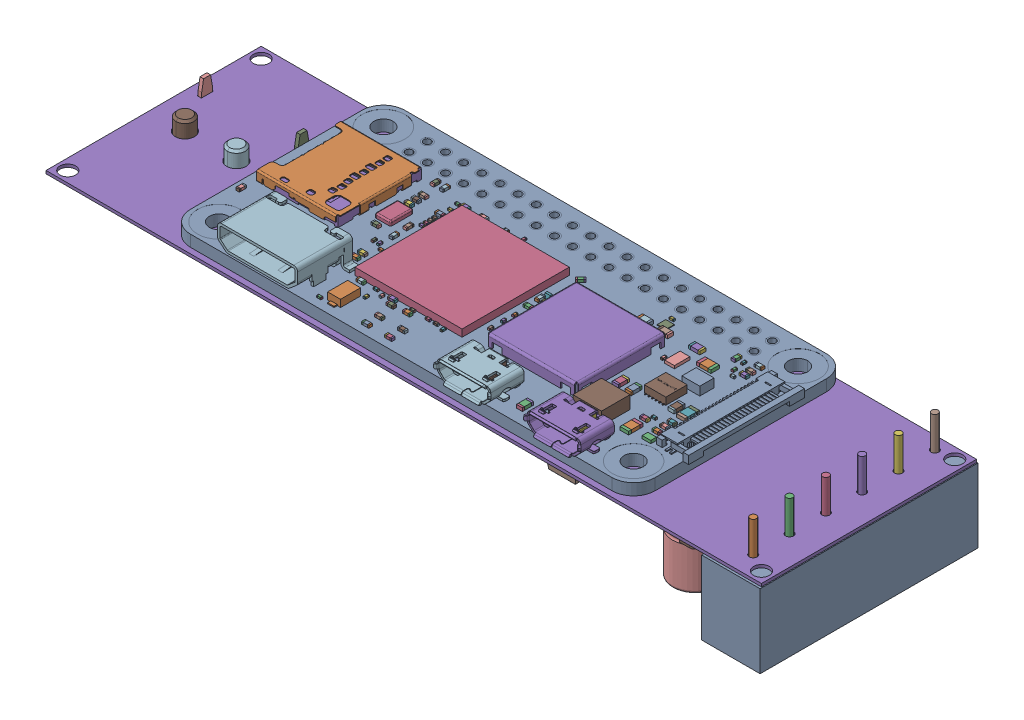
SolidWorks assembly pcb, configuration cage. Lengths in mm.
Overall size (100.11 16.86 31.05).
60 component instances, 5 part files, 37 mates.
Components (placement in the parent):
- Raspberry Pi Zero 2 W-1: Raspberry Pi Zero 2 W [Default] at origin size (65.8 5.05 30.58)
- custom_pcb-1: custom_pcb [Default] at (-49.911 -2.2115 14.789) x (1 0 0) z (0 -1 0) size (100.11 30.48 15.4)
- spacer-2: spacer [m3 1-8] at (-29 -3.975 11.5) x (0.982082 0 -0.188455) z (0.188455 0 0.982082) (suppressed, hidden)
- spacer-5: spacer [m3 0.4] at (-29 -14.5465 -11.5) x (0.8 0 -0.6) z (0.6 0 0.8) (suppressed, hidden)
- spacer-6: spacer [m3 0.4] at (29 -14.5465 -11.5) x (0.672593 0 -0.740013) z (0.740013 0 0.672593) (suppressed, hidden)
- spacer-7: spacer [m3 0.4] at (29 -14.5465 11.5) x (0.497251 0 -0.867606) z (0.867606 0 0.497251) (suppressed, hidden)
- spacer-8: spacer [m3 0.4] at (-29 -14.5465 11.5) x (0.28 0 -0.96) z (0.96 0 0.28) (suppressed, hidden)
- DRV8871-1: DRV8871 [Default] at (-7.62 8.6837 12.7) x (-1 0 0) z (0 1 0) (suppressed, hidden)
- plate-1: plate [Default] at (0 4.7588 0) (suppressed, hidden)
- spacer-17: spacer [m3 1-32] at (-29 3.965 11.5) x (-0.952427 0 0.304765) z (-0.304765 0 -0.952427) (suppressed, hidden)
- spacer-19: spacer [m3 1-32] at (-29 3.1713 11.5) x (-0.952427 0 0.304765) z (-0.304765 0 -0.952427) (suppressed, hidden)
- spacer-20: spacer [m3 1-32] at (-29 2.3775 11.5) x (-0.952427 0 0.304765) z (-0.304765 0 -0.952427) (suppressed, hidden)
- spacer-21: spacer [m3 1-32] at (-29 1.5837 11.5) x (-0.952427 0 0.304765) z (-0.304765 0 -0.952427) (suppressed, hidden)
- spacer-22: spacer [m3 1-32] at (-29 0.79 11.5) x (-0.952427 0 0.304765) z (-0.304765 0 -0.952427) (suppressed, hidden)
- spacer-23: spacer [m3 1-32] at (29 -1.5938 -11.5) x (0.982082 0 -0.188455) z (0.188455 0 0.982082) (suppressed, hidden)
- spacer-24: spacer [m3 1-32] at (29 -1.5938 11.5) x (0.982082 0 -0.188455) z (0.188455 0 0.982082) (suppressed, hidden)
- spacer-25: spacer [m3 1-32] at (-29 -1.5938 -11.5) x (0.982082 0 -0.188455) z (0.188455 0 0.982082) (suppressed, hidden)
- spacer-26: spacer [m3 1-32] at (29 3.965 -11.5) x (-0.952427 0 0.304765) z (-0.304765 0 -0.952427) (suppressed, hidden)
- spacer-27: spacer [m3 1-32] at (29 3.965 11.5) x (-0.952427 0 0.304765) z (-0.304765 0 -0.952427) (suppressed, hidden)
- spacer-28: spacer [m3 1-32] at (-29 3.965 -11.5) x (-0.952427 0 0.304765) z (-0.304765 0 -0.952427) (suppressed, hidden)
- spacer-29: spacer [m3 1-32] at (29 3.1713 -11.5) x (-0.952427 0 0.304765) z (-0.304765 0 -0.952427) (suppressed, hidden)
- spacer-30: spacer [m3 1-32] at (29 3.1713 11.5) x (-0.952427 0 0.304765) z (-0.304765 0 -0.952427) (suppressed, hidden)
- spacer-31: spacer [m3 1-32] at (-29 3.1713 -11.5) x (-0.952427 0 0.304765) z (-0.304765 0 -0.952427) (suppressed, hidden)
- spacer-32: spacer [m3 1-32] at (29 2.3775 -11.5) x (-0.952427 0 0.304765) z (-0.304765 0 -0.952427) (suppressed, hidden)
- spacer-33: spacer [m3 1-32] at (29 2.3775 11.5) x (-0.952427 0 0.304765) z (-0.304765 0 -0.952427) (suppressed, hidden)
- spacer-34: spacer [m3 1-32] at (-29 2.3775 -11.5) x (-0.952427 0 0.304765) z (-0.304765 0 -0.952427) (suppressed, hidden)
- spacer-35: spacer [m3 1-32] at (29 1.5837 -11.5) x (-0.952427 0 0.304765) z (-0.304765 0 -0.952427) (suppressed, hidden)
- spacer-36: spacer [m3 1-32] at (29 1.5837 11.5) x (-0.952427 0 0.304765) z (-0.304765 0 -0.952427) (suppressed, hidden)
- spacer-37: spacer [m3 1-32] at (-29 1.5837 -11.5) x (-0.952427 0 0.304765) z (-0.304765 0 -0.952427) (suppressed, hidden)
- spacer-38: spacer [m3 1-32] at (29 0.79 -11.5) x (-0.952427 0 0.304765) z (-0.304765 0 -0.952427) (suppressed, hidden)
- spacer-39: spacer [m3 1-32] at (29 0.79 11.5) x (-0.952427 0 0.304765) z (-0.304765 0 -0.952427) (suppressed, hidden)
- spacer-40: spacer [m3 1-32] at (-29 0.79 -11.5) x (-0.952427 0 0.304765) z (-0.304765 0 -0.952427) (suppressed, hidden)
- spacer-45: spacer [m2 1-32] at (-15.24 7.14 3.175) x (-0.952427 0 0.304765) z (-0.304765 0 -0.952427) (suppressed, hidden)
- DRV8871-7: DRV8871 [Default] at (13.97 8.6837 12.7) x (-1 0 0) z (0 1 0) (suppressed, hidden)
- spacer-51: spacer [m2 1-32] at (-15.24 6.3463 3.175) x (-0.952427 0 0.304765) z (-0.304765 0 -0.952427) (suppressed, hidden)
- spacer-52: spacer [m2 1-32] at (30.48 8.7275 3.4925) x (0.400623 0 0.916243) z (-0.916243 0 0.400623) (suppressed, hidden)
- spacer-53: spacer [m2 1-32] at (30.48 8.7275 18.7325) x (0.400623 0 0.916243) z (-0.916243 0 0.400623) (suppressed, hidden)
- spacer-54: spacer [m2 1-32] at (30.48 8.7275 -18.7325) x (0.400623 0 0.916243) z (-0.916243 0 0.400623) (suppressed, hidden)
- spacer-55: spacer [m2 1-32] at (30.48 8.7275 -3.4925) x (0.400623 0 0.916243) z (-0.916243 0 0.400623) (suppressed, hidden)
- spacer-56: spacer [m2 1-32] at (5.08 8.7275 -18.7325) x (0.400623 0 0.916243) z (-0.916243 0 0.400623) (suppressed, hidden)
- spacer-57: spacer [m2 1-32] at (30.48 7.9337 3.4925) x (0.400623 0 0.916243) z (-0.916243 0 0.400623) (suppressed, hidden)
- spacer-58: spacer [m2 1-32] at (30.48 7.9337 18.7325) x (0.400623 0 0.916243) z (-0.916243 0 0.400623) (suppressed, hidden)
- spacer-59: spacer [m2 1-32] at (30.48 7.9337 -18.7325) x (0.400623 0 0.916243) z (-0.916243 0 0.400623) (suppressed, hidden)
- spacer-60: spacer [m2 1-32] at (30.48 7.9337 -3.4925) x (0.400623 0 0.916243) z (-0.916243 0 0.400623) (suppressed, hidden)
- spacer-61: spacer [m2 1-32] at (5.08 7.9337 -18.7325) x (0.400623 0 0.916243) z (-0.916243 0 0.400623) (suppressed, hidden)
- spacer-62: spacer [m2 1-32] at (21.59 7.14 -3.175) x (-0.952427 0 0.304765) z (-0.304765 0 -0.952427) (suppressed, hidden)
- spacer-63: spacer [m2 1-32] at (6.35 7.14 -3.175) x (-0.952427 0 0.304765) z (-0.304765 0 -0.952427) (suppressed, hidden)
- spacer-64: spacer [m2 1-32] at (0 7.14 3.175) x (-0.952427 0 0.304765) z (-0.304765 0 -0.952427) (suppressed, hidden)
- spacer-65: spacer [m2 1-32] at (-15.24 7.14 -3.175) x (-0.952427 0 0.304765) z (-0.304765 0 -0.952427) (suppressed, hidden)
- spacer-66: spacer [m2 1-32] at (0 7.14 -3.175) x (-0.952427 0 0.304765) z (-0.304765 0 -0.952427) (suppressed, hidden)
- spacer-67: spacer [m2 1-32] at (21.59 6.3463 -3.175) x (-0.952427 0 0.304765) z (-0.304765 0 -0.952427) (suppressed, hidden)
- spacer-68: spacer [m2 1-32] at (6.35 6.3463 -3.175) x (-0.952427 0 0.304765) z (-0.304765 0 -0.952427) (suppressed, hidden)
- spacer-69: spacer [m2 1-32] at (0 6.3463 3.175) x (-0.952427 0 0.304765) z (-0.304765 0 -0.952427) (suppressed, hidden)
- spacer-70: spacer [m2 1-32] at (-15.24 6.3463 -3.175) x (-0.952427 0 0.304765) z (-0.304765 0 -0.952427) (suppressed, hidden)
- spacer-71: spacer [m2 1-32] at (0 6.3463 -3.175) x (-0.952427 0 0.304765) z (-0.304765 0 -0.952427) (suppressed, hidden)
- DRV8871-9: DRV8871 [Default] at (13.97 8.6837 -12.7) x (1 0 0) z (0 1 0) (suppressed, hidden)
- spacer-72: spacer [m2 1-32] at (21.59 7.14 3.175) x (-0.952427 0 0.304765) z (-0.304765 0 -0.952427) (suppressed, hidden)
- spacer-73: spacer [m2 1-32] at (6.35 7.14 3.175) x (-0.952427 0 0.304765) z (-0.304765 0 -0.952427) (suppressed, hidden)
- spacer-74: spacer [m2 1-32] at (21.59 6.3463 3.175) x (-0.952427 0 0.304765) z (-0.304765 0 -0.952427) (suppressed, hidden)
- spacer-75: spacer [m2 1-32] at (6.35 6.3463 3.175) x (-0.952427 0 0.304765) z (-0.304765 0 -0.952427) (suppressed, hidden)
Mates (geometry in assembly coordinates):
- Coincident30: coordinate: point of Raspberry Pi Zero 2 W-1
- Concentric1: concentric aligned: cylinder of Raspberry Pi Zero 2 W-1 through (-24.13 0.8 -12.77) axis (0 1 0) radius 0.5; cylinder of custom_pcb-1 through (-24.13 -1.8 -12.77) axis (0 1 0) radius 0.555
- Parallel1: parallel aligned: plane of Raspberry Pi Zero 2 W-1 through (-32.5 0.8 -15) normal (0 0 -1); plane of custom_pcb-1 through (-49.911 -1.8 -15.31) normal (0 0 -1)
- Coincident33: coincident anti-aligned: plane of Raspberry Pi Zero 2 W-1 through (0 -0.8 0) normal (0 -1 0); plane of spacer-2 through (-29 -0.8 11.5) normal (0 1 0)
- Coincident34: coincident anti-aligned: plane of custom_pcb-1 through (0.127 -1.8 -0.2605) normal (0 1 0); plane of spacer-2 through (-29 -3.975 11.5) normal (0 -1 0)
- Concentric4: concentric anti-aligned: cylinder of Raspberry Pi Zero 2 W-1 through (-29 0.8 11.5) axis (0 1 0) radius 1.35; cylinder of spacer-2 through (-29 -0.8 11.5) axis (0 -1 0) radius 3.175
- Coincident39: coincident anti-aligned: plane of custom_pcb-1 through (0.127 -2.2115 -0.2605) normal (0 -1 0); plane of spacer-5 through (-29 -4.3865 -11.5) normal (0 1 0)
- Coincident40: coincident anti-aligned: plane of custom_pcb-1 through (0.127 -2.2115 -0.2605) normal (0 -1 0); plane of spacer-6 through (29 -4.3865 -11.5) normal (0 1 0)
- Coincident41: coincident anti-aligned: plane of custom_pcb-1 through (0.127 -2.2115 -0.2605) normal (0 -1 0); plane of spacer-7 through (29 -4.3865 11.5) normal (0 1 0)
- Coincident42: coincident anti-aligned: plane of custom_pcb-1 through (0.127 -2.2115 -0.2605) normal (0 -1 0); plane of spacer-8 through (-29 -4.3865 11.5) normal (0 1 0)
- Concentric10: concentric aligned: cylinder of spacer-2 through (-29 -0.8 11.5) axis (0 -1 0) radius 3.175; cylinder of spacer-8 through (-29 -4.3865 11.5) axis (0 -1 0) radius 3.175
- Concentric12: concentric aligned: cylinder of Raspberry Pi Zero 2 W-1 through (-29 0.8 11.5) axis (0 1 0) radius 1.35; cylinder of plate-1 through (-29 6.3463 11.5) axis (0 1 0) radius 1.7
- Parallel2: parallel aligned: plane of Raspberry Pi Zero 2 W-1 through (-32.5 0.8 15) normal (0 0 1); plane of plate-1 through (-34.925 6.3463 22.225) normal (0 0 1)
- Coincident48: coincident anti-aligned: plane of plate-1 through (0 4.7588 0) normal (0 -1 0); plane of spacer-17 through (-29 4.7588 11.5) normal (0 1 0)
- Concentric16: concentric anti-aligned: cylinder of plate-1 through (-29 6.3463 11.5) axis (0 1 0) radius 1.7; cylinder of spacer-17 through (-29 4.7588 11.5) axis (0 -1 0) radius 3.175
- Coincident53: coincident anti-aligned: plane of Raspberry Pi Zero 2 W-1 through (-29 0.79 11.5) normal (0 1 0); plane of spacer-22 through (-29 0.79 11.5) normal (0 -1 0)
- Coincident56: coincident anti-aligned: plane of DRV8871-1 through (-7.62 7.9337 12.7) normal (0 -1 0); plane of spacer-45 through (-15.24 7.9337 3.175) normal (0 1 0)
- Concentric21: concentric anti-aligned: cylinder of spacer-49 through (-6.8904 9.5213 7.6284) axis (0 1 0) radius 1.2; cylinder of DRV8871-7 through (21.59 9.4337 3.175) axis (0 -1 0) radius 1.27
- Coincident57: coincident anti-aligned: plane of spacer-49 through (-6.8904 9.5213 7.6284) normal (0 1 0); plane of DRV8871-7 through (13.97 7.9337 12.7) normal (0 -1 0)
- Coincident59: coincident anti-aligned: plane of plate-1 through (0 6.3463 0) normal (0 1 0); plane of spacer-51 through (-15.24 6.3463 3.175) normal (0 -1 0)
- Concentric23: concentric anti-aligned: cylinder of DRV8871-7 through (21.59 9.4337 3.175) axis (0 -1 0) radius 1.27; cylinder of spacer-55 through (30.48 9.5213 -3.4925) axis (0 1 0) radius 1.2
- Coincident60: coincident anti-aligned: plane of DRV8871-7 through (13.97 7.9337 12.7) normal (0 -1 0); plane of spacer-55 through (30.48 9.5213 -3.4925) normal (0 1 0)
- Concentric26: concentric anti-aligned: cylinder of DRV8871-7 through (6.35 9.4337 3.175) axis (0 -1 0) radius 1.27; cylinder of spacer-54 through (30.48 9.5213 -18.7325) axis (0 1 0) radius 1.2
- Concentric27: concentric anti-aligned: cylinder of DRV8871-1 through (-15.24 9.4337 3.175) axis (0 -1 0) radius 1.27; cylinder of spacer-56 through (5.08 9.5213 -18.7325) axis (0 1 0) radius 1.2
- Concentric29: concentric anti-aligned: cylinder of plate-1 through (-15.24 6.3463 3.175) axis (0 1 0) radius 0.8; cylinder of spacer-51 through (-15.24 7.14 3.175) axis (0 -1 0) radius 2.3813
- Concentric30: concentric aligned: cylinder of DRV8871-1 through (-15.24 9.4337 3.175) axis (0 -1 0) radius 1.27; cylinder of spacer-45 through (-15.24 7.9337 3.175) axis (0 -1 0) radius 2.3813
- Concentric31: concentric anti-aligned: cylinder of DRV8871-1 through (0 9.4337 3.175) axis (0 -1 0) radius 1.27; cylinder of spacer-64 through (0 7.9337 3.175) axis (0 1 0) radius 1.2
- Coincident63: coincident anti-aligned: plane of spacer-66 through (0 7.9337 -3.175) normal (0 1 0); plane of DRV8871-9 through (-3.4601 13.4664 -12.4261) normal (0 -1 0)
- Concentric34: concentric anti-aligned: cylinder of spacer-66 through (0 7.9337 -3.175) axis (0 1 0) radius 1.2; cylinder of DRV8871-9 through (0 9.4337 -3.175) axis (0 -1 0) radius 1.27
- Concentric35: concentric anti-aligned: cylinder of spacer-65 through (-15.24 7.9337 -3.175) axis (0 1 0) radius 1.2; cylinder of DRV8871-9 through (-15.24 9.4337 -3.175) axis (0 -1 0) radius 1.27
- Concentric36: concentric anti-aligned: cylinder of DRV8871-7 through (21.59 9.4337 3.175) axis (0 -1 0) radius 1.27; cylinder of spacer-72 through (21.59 7.9337 3.175) axis (0 1 0) radius 1.2
- Concentric37: concentric anti-aligned: cylinder of DRV8871-7 through (6.35 9.4337 3.175) axis (0 -1 0) radius 1.27; cylinder of spacer-73 through (6.35 7.9337 3.175) axis (0 1 0) radius 1.2
- Coincident64: coincident anti-aligned: plane of DRV8871-7 through (13.97 7.9337 12.7) normal (0 -1 0); plane of spacer-73 through (6.35 7.9337 3.175) normal (0 1 0)
- Concentric38: concentric: cylinder of spacer-63 through (6.35 7.9337 -3.175) axis (0 1 0) radius 1.2; cylinder of DRV8871-9 through (6.3499 9.4838 -3.2057) axis (0 -1 0) radius 1.27
- Coincident65: coincident: plane of spacer-63 through (6.35 7.9337 -3.175) normal (0 1 0); plane of DRV8871-9 through (13.6351 7.9837 -12.9892) normal (0 -1 0)
- Concentric39: concentric anti-aligned: cylinder of spacer-62 through (21.59 7.9337 -3.175) axis (0 1 0) radius 1.2; cylinder of DRV8871-9 through (21.5808 9.4838 -3.7341) axis (0 -1 0) radius 1.27
- Distance1: distance = 1 mm anti-aligned: plane of Raspberry Pi Zero 2 W-1 through (0 -0.8 0) normal (0 -1 0); plane of custom_pcb-1 through (0.127 -1.8 -0.2605) normal (0 1 0)
